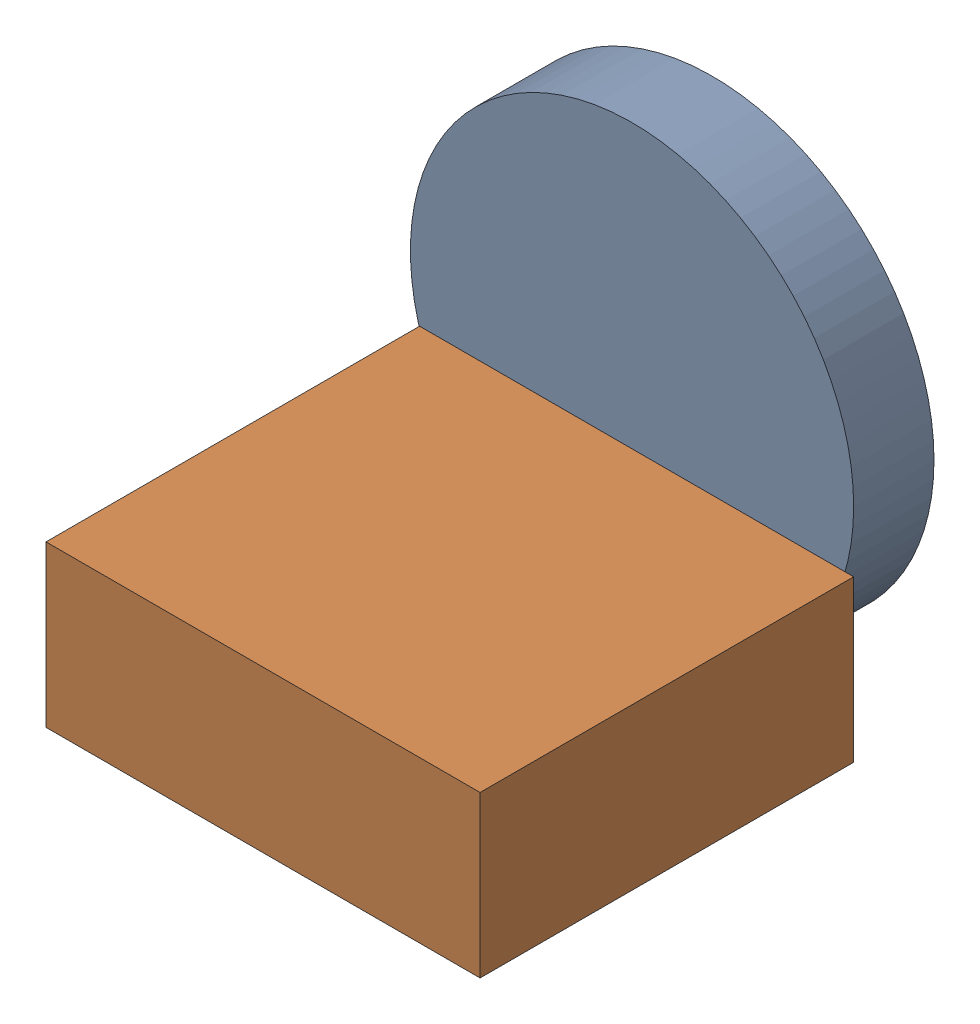
SolidWorks assembly Assem1, configuration Default. Lengths in mm.
Overall size (55.17 55.17 62.23).
3 component instances, 3 part files, 5 mates.
Components (placement in the parent):
- Part1-1: Part1 [Default] at (-24.8178 11.3429 7.7042) size (55.17 55.17 10)
- Part2-1: Part2 [Default] at (-25.2044 -13.3142 44.4214) x (1 0 0) z (0 1 0) size (54.03 46.5 20)
- ISO 7380-1 M3x4mm v7-1: ISO 7380-1 M3x4mm v7 [Default] at (-31.2132 14.2716 6.0542) size (5.7 5.7 5.73)
Mates (geometry in assembly coordinates):
- Concentric1: concentric anti-aligned: circle of Part1-1; circle of ISO 7380-1 M3x4mm v7-1
- Coincident1: coincident anti-aligned: plane of Part1-1 through (-31.2132 14.2716 7.7042) normal (0 0 -1); plane of ISO 7380-1 M3x4mm v7-1 through (-31.2132 16.0962 7.7042) normal (0 0 1)
- Coincident2: coincident anti-aligned: plane of Part1-1 through (-31.2132 14.2716 17.7042) normal (0 0 1); plane of Part2-1 through (-57.6595 6.6858 17.7042) normal (0 0 -1)
- Tangent1: tangent aligned: cylinder of Part1-1 through (-31.2132 14.2716 17.7042) axis (0 0 -1) radius 27.5858; plane of Part2-1 through (-25.2044 -13.3142 44.4214) normal (0 -1 0)
- Tangent2: tangent aligned: cylinder of Part1-1 through (-31.2132 14.2716 17.7042) axis (0 0 -1) radius 27.5858; plane of Part2-1 through (-3.6275 6.6858 64.2053) normal (1 0 0)
